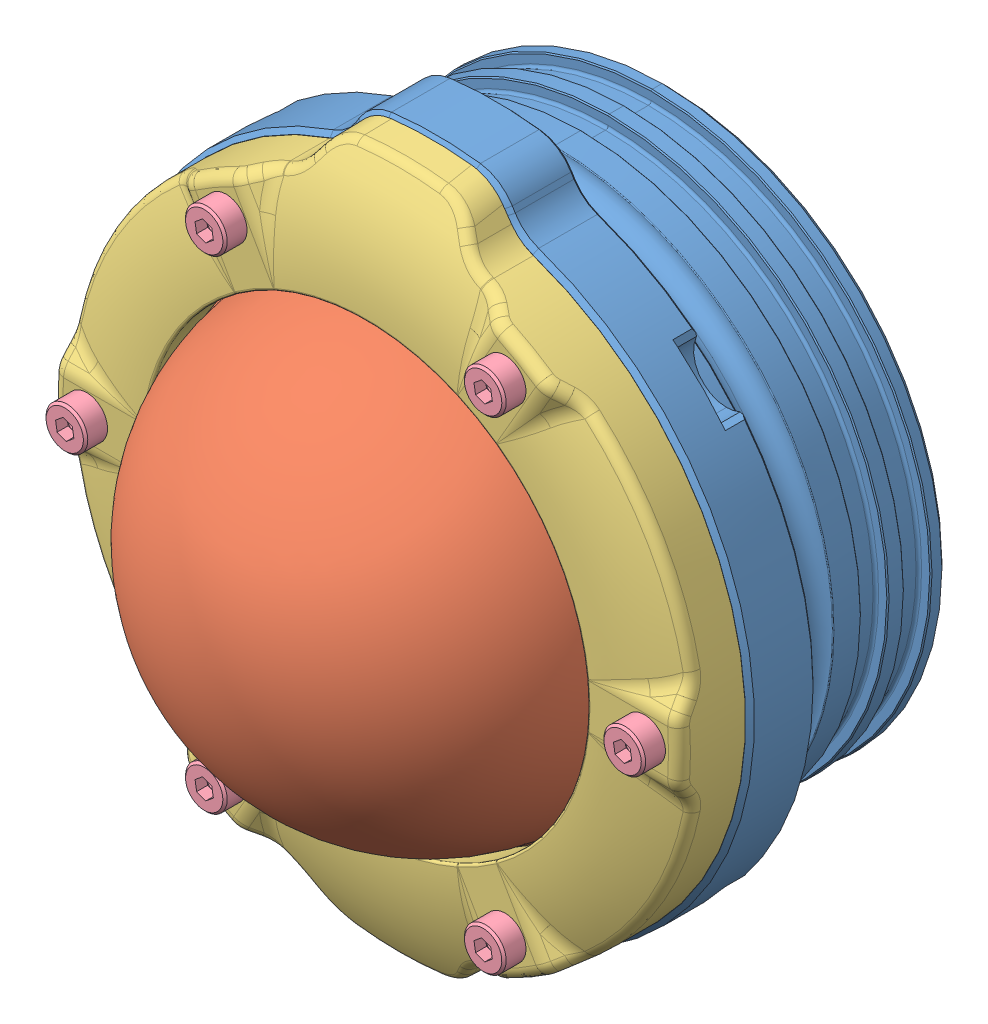
SolidWorks assembly cap-dome, configuration Default. Lengths in mm.
Overall size (79.03 79.72 42.2).
9 component instances, 4 part files, 7 mates.
Components (placement in the parent):
- WTE2-M-LOCKING-FLANGE-SEAL-R1-1: WTE2-M-LOCKING-FLANGE-SEAL-R1 [Default] at origin size (58 63.5 21.5)
- WTE2-P-DOME-R1-1: WTE2-P-DOME-R1 [Default] at (0 0 21.7) x (0.957614 0.288054 0) z (0.288054 -0.957614 0) size (48.5 20.5 48.5)
- WTE2-P-RETAINING-RING-R1-1: WTE2-P-RETAINING-RING-R1 [Default] at (0 0 21.5) x (-0.5 0.866025 0) z (0.866025 0.5 0) size (59.06 6.65 57.16)
- socket head cap screw_am-1: socket head cap screw_am [B18.3.1M - 2 x 0.4 x 10 Hex SHCS -- 10CHX] at (-12.7 21.997 29.5) x (0 0 -1) z (-0.351838 -0.936061 0) size (12 3.8 3.8)
- socket head cap screw_am-2: socket head cap screw_am [B18.3.1M - 2 x 0.4 x 10 Hex SHCS -- 10CHX] at (-25.4 0 29.5) x (0 0 -1) z (0.634734 -0.772731 0) size (12 3.8 3.8)
- socket head cap screw_am-3: socket head cap screw_am [B18.3.1M - 2 x 0.4 x 10 Hex SHCS -- 10CHX] at (-12.7 -21.997 29.5) x (0 0 -1) z (0.986571 0.16333 0) size (12 3.8 3.8)
- socket head cap screw_am-4: socket head cap screw_am [B18.3.1M - 2 x 0.4 x 10 Hex SHCS -- 10CHX] at (12.7 -21.997 29.5) x (0 0 -1) z (0.351838 0.936061 0) size (12 3.8 3.8)
- socket head cap screw_am-5: socket head cap screw_am [B18.3.1M - 2 x 0.4 x 10 Hex SHCS -- 10CHX] at (25.4 0 29.5) x (0 0 -1) z (-0.634734 0.772731 0) size (12 3.8 3.8)
- socket head cap screw_am-6: socket head cap screw_am [B18.3.1M - 2 x 0.4 x 10 Hex SHCS -- 10CHX] at (12.7 21.997 29.5) x (0 0 -1) z (-0.986571 -0.16333 0) size (12 3.8 3.8)
Mates (geometry in assembly coordinates):
- Concentric1: concentric anti-aligned: cylinder of WTE2-M-LOCKING-FLANGE-SEAL-R1-1 through (0 0 22.82) axis (0 0 -1) radius 22.9108; cone of WTE2-P-DOME-R1-1 through (0 0 21.7) axis (0 0 1)
- Concentric2: concentric anti-aligned: cylinder of WTE2-M-LOCKING-FLANGE-SEAL-R1-1 through (0 0 22.82) axis (0 0 -1) radius 22.9108; cone of WTE2-P-RETAINING-RING-R1-1 through (0 0 27.5) axis (0 0 1)
- Coincident1: coincident anti-aligned: plane of WTE2-P-DOME-R1-1 through (23.0127 6.9223 24.2) normal (0 0 1); plane of WTE2-P-RETAINING-RING-R1-1 through (-12.1319 21.0131 24.2) normal (0 0 -1)
- Coincident2: coincident anti-aligned: plane of WTE2-M-LOCKING-FLANGE-SEAL-R1-1 through (0 0 21.5) normal (0 0 1); plane of WTE2-P-RETAINING-RING-R1-1 through (-12.25 21.2176 21.5) normal (0 0 -1)
- Concentric4: concentric aligned: cylinder of WTE2-M-LOCKING-FLANGE-SEAL-R1-1 through (-12.7 -21.997 21.5) axis (0 0 1) radius 0.8; cylinder of WTE2-P-RETAINING-RING-R1-1 through (-12.7 -21.997 21.5) axis (0 0 1) radius 1.1
- Concentric5: concentric aligned: cylinder of WTE2-P-RETAINING-RING-R1-1 through (-12.7 21.997 21.5) axis (0 0 1) radius 1.1; cylinder of M2x10-screw-1 through (-12.7 21.997 61.25) axis (0 0 1) radius 1
- Coincident3: coincident anti-aligned: plane of WTE2-P-RETAINING-RING-R1-1 through (-13.4955 28.6749 27.5) normal (0 0 1); plane of M2x10-screw-1 through (-10.9215 21.3286 27.5) normal (0 0 -1)
